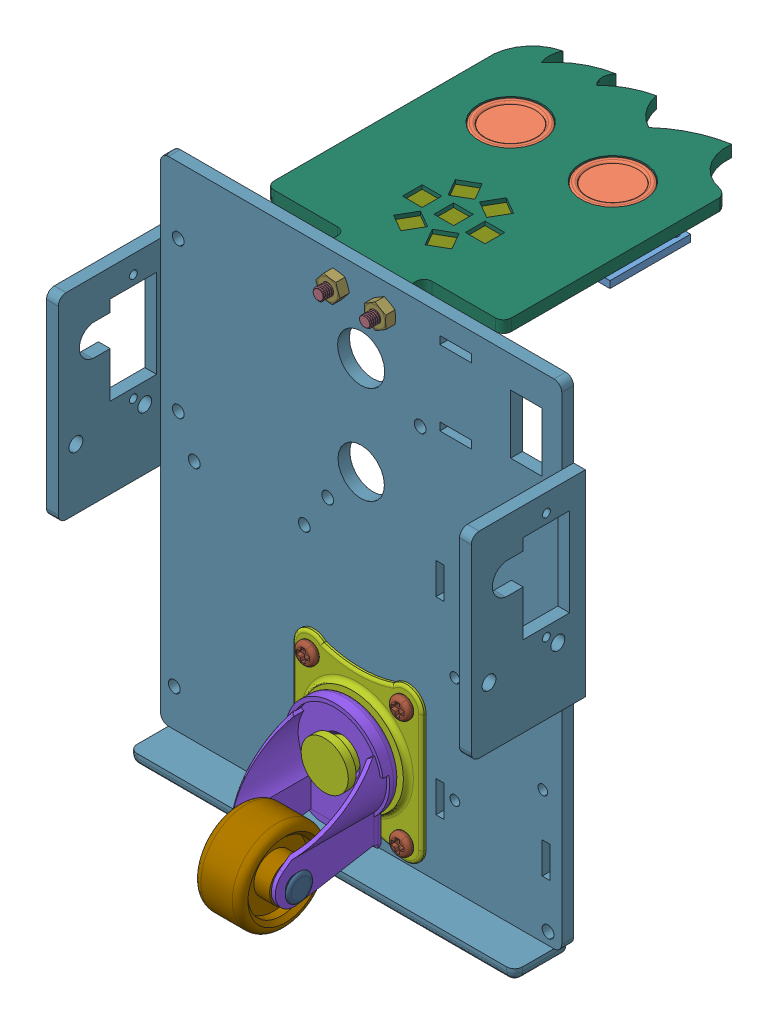
SolidWorks assembly DYOR_3D_LS, configuration Predeterminado. Lengths in mm.
Overall size (108 131.39 112.97).
36 component instances, 16 part files, 16 mates.
Components (placement in the parent):
- HC-SR04 Ping Sensor-1: HC-SR04 Ping Sensor [Default] at (9.418 28.7888 -38.4611) x (0 0 -1) z (0 1 0) size (25.18 45 18.07)
  - PCB-1: PCB [Default] at origin size (20.5 45 1.75)
  - Transducer-1: Transducer [Default] at (0 -13 13.25) x (1 0 0) z (0 -1 0) size (15.88 12 15.88)
  - Transducer-2: Transducer [Default] at (0 13 13.25) x (1 0 0) z (0 -1 0) size (15.88 12 15.88)
  - 3 Pin Header 90 Degree-1: 3 Pin Header 90 Degree [Default] at (8.4275 0 -1.25) x (-1 0 0) z (0 -1 0) size (8 7.82 10)
  - 14 Pin SMT-1: 14 Pin SMT [Default] at (-0.35 -18.5 -0.85) x (0 -1 0) z (1 0 0) size (6 1.6 8.8)
  - 14 Pin SMT-2: 14 Pin SMT [Default] at (0 -0.3826 -0.85) x (1 0 0) z (0 1 0) size (6 1.6 8.8)
  - 14 Pin SMT-3: 14 Pin SMT [Default] at (0 17.5274 -0.85) x (1 0 0) z (0 1 0) size (6 1.6 8.8)
  - Cap1 SMT-1: Cap1 SMT [Default] at (-1.755 7.4774 -0.9689) x (0 1 0) z (-1 0 0) size (4.5 1.84 1.75)
  - Cap1 SMT-2: Cap1 SMT [Default] at (6.835 7.4774 -0.9689) x (0 1 0) z (-1 0 0) size (4.5 1.84 1.75)
  - Cap1 SMT-3: Cap1 SMT [Default] at (-6.835 7.4774 -0.9689) x (0 1 0) z (-1 0 0) size (4.5 1.84 1.75)
  - Cap1 SMT-4: Cap1 SMT [Default] at (4.295 7.4774 -0.9689) x (0 1 0) z (-1 0 0) size (4.5 1.84 1.75)
  - Cap1 SMT-5: Cap1 SMT [Default] at (1.755 7.4774 -0.9689) x (0 1 0) z (-1 0 0) size (4.5 1.84 1.75)
  - Cap1 SMT-6: Cap1 SMT [Default] at (-4.295 7.4774 -0.9689) x (0 1 0) z (-1 0 0) size (4.5 1.84 1.75)
  - HC-SR04 Crystal-1: HC-SR04 Crystal [Default] at (-8.3 0 1.75) x (0 -1 0) z (0 0 1) size (10 3.5 2.7)
- CA-1: CA [Predeterminado] at (-2.207 18.0036 0) size (33 45.94 43.2)
  - Caster Wheel-1: Caster Wheel [Default] at (57.6387 -78.841 57.7572) x (0 1 0) z (-1 0 0) size (45.94 37.59 33)
    - caster holder-1: caster holder [Default] at (-24.0751 44.7184 29.5137) x (1 0 0) z (0 0 -1) size (39 9.27 33)
    - holder-1: holder [Default] at (-1.5751 42.9484 46.0137) x (0 0 1) z (1 0 0) size (25 28.07 31.31)
    - caster wheel-1: caster wheel [Default] at (-15.6961 19.9484 46.0137) x (0.997275 0.073773 0) z (0 0 1) size (23 23 14)
    - Part4-1: Part4 [Default] at (-15.6961 19.9484 55.0137) x (-0.978448 0.206495 0) z (0 0 -1) size (7 7 20)
  - M3x6 Philips Screw-1: M3x6 Philips Screw [Predeterminado] at (23.625 -65.4161 13.5389) size (5.3 5.3 7.81)
  - M3x6 Philips Screw-2: M3x6 Philips Screw [Predeterminado] at (-0.375 -65.4161 13.5389) size (5.3 5.3 7.81)
  - M3x6 Philips Screw-3: M3x6 Philips Screw [Predeterminado] at (-0.375 -95.4161 13.5389) size (5.3 5.3 7.81)
  - M3x6 Philips Screw-4: M3x6 Philips Screw [Predeterminado] at (23.625 -95.4161 13.5389) size (5.3 5.3 7.81)
  - M3 Nut-1: M3 Nut [Predeterminado] at (23.625 -65.4161 11.0389) size (6.27 6.27 2.71)
  - M3 Nut-2: M3 Nut [Predeterminado] at (-0.375 -65.4161 11.0389) size (6.27 6.27 2.71)
  - M3 Nut-3: M3 Nut [Predeterminado] at (-0.375 -95.4161 11.0389) size (6.27 6.27 2.71)
  - M3 Nut-4: M3 Nut [Predeterminado] at (23.625 -95.4161 11.0389) size (6.27 6.27 2.71)
- M3x10 Philips Screw-2: M3x10 Philips Screw [Predeterminado] at (3.418 36.0388 7.5389) x (-0.665771 0.746156 0) z (0 0 -1) size (5.3 5.3 11.8)
- M3x10 Philips Screw-3: M3x10 Philips Screw [Predeterminado] at (15.418 36.0388 7.5389) x (0.006663 -0.999978 0) z (0 0 -1) size (5.3 5.3 11.8)
- M3 Nut-1: M3 Nut [Predeterminado] at (3.418 36.0388 16.5389) x (0.934299 0.356491 0) z (0 0 1) size (6.27 6.27 2.71)
- M3 Nut-2: M3 Nut [Predeterminado] at (15.418 36.0388 11.0389) x (-0.487763 -0.872976 0) z (0 0 -1) size (6.27 6.27 2.71)
- Base-1: Base [Predeterminado] at (60.418 -80.9125 12.5389) size (108 128.45 29)
- Front_LS-1: Front_LS [Predeterminado] at (-51.2809 39.5388 -46.4821) x (1 0 0) z (0 1 0) size (60.34 72.38 11)
- ws8212-7-1: ws8212-7 [Predeterminado] at (9.418 38.5388 -10.9611) x (0 0 -1) z (0 1 0) size (24 24 3.1)
Mates (geometry in assembly coordinates):
- Concéntrica15: concentric: circle of CA-1/Caster Wheel-1/caster holder-1; circle of Base-1
- Coincidente14: coincident: plane of CA-1/M3 Nut-4 through (21.418 -77.4125 9.5389) normal (0 0 1); plane of Base-1 through (-39.582 40.5388 9.5389) normal (0 0 -1)
- Concéntrica16: concentric: circle of CA-1/M3 Nut-1; circle of Base-1
- Concéntrica22: concentric: circle of M3x10 Philips Screw-2; circle of Base-1
- Concéntrica23: concentric: circle of M3 Nut-1; circle of Base-1
- Concéntrica24: concentric: circle of M3 Nut-2; circle of Base-1
- Coincidente31: coincident: plane of M3 Nut-1 through (3.418 36.0388 12.5389) normal (0 0 -1); plane of Base-1 through (-39.582 40.5388 12.5389) normal (0 0 1)
- Coincidente32: coincident: plane of M3 Nut-2 through (15.418 36.0388 12.5389) normal (0 0 -1); plane of Base-1 through (-39.582 40.5388 12.5389) normal (0 0 1)
- Coincidente33: coincident: plane of Base-1 through (-39.582 40.5388 9.5389) normal (0 0 -1); plane of Front_LS-1 through (-0.582 42.5388 9.5389) normal (0 0 1)
- Concéntrica25: concentric: circle of Base-1; circle of Front_LS-1
- Concéntrica26: concentric: circle of HC-SR04 Ping Sensor-1/Transducer-1; circle of Front_LS-1
- Coincidente34: coincident: plane of HC-SR04 Ping Sensor-1/Transducer-2 through (-3.582 42.5388 -46.4011) normal (0 1 0); plane of Front_LS-1 through (-2.582 42.5388 8.5389) normal (0 1 0)
- Concéntrica27: concentric: circle of HC-SR04 Ping Sensor-1/Transducer-2; circle of Front_LS-1
- Coincidente35: coincident: plane of Front_LS-1 through (3.918 42.5388 -8.4611) normal (-1 0 0); plane of ws8212-7-1 through (3.918 41.5388 -13.4611) normal (1 0 0)
- Coincidente36: coincident: plane of Front_LS-1 through (-1.082 42.5388 -8.4611) normal (0 0 -1); plane of ws8212-7-1 through (-1.082 41.5388 -8.4611) normal (0 0 1)
- Distancia1: distance = 1 mm: plane of ws8212-7-1 through (9.418 41.5388 -10.9611) normal (0 1 0); plane of Front_LS-1 through (-2.582 42.5388 8.5389) normal (0 1 0)
